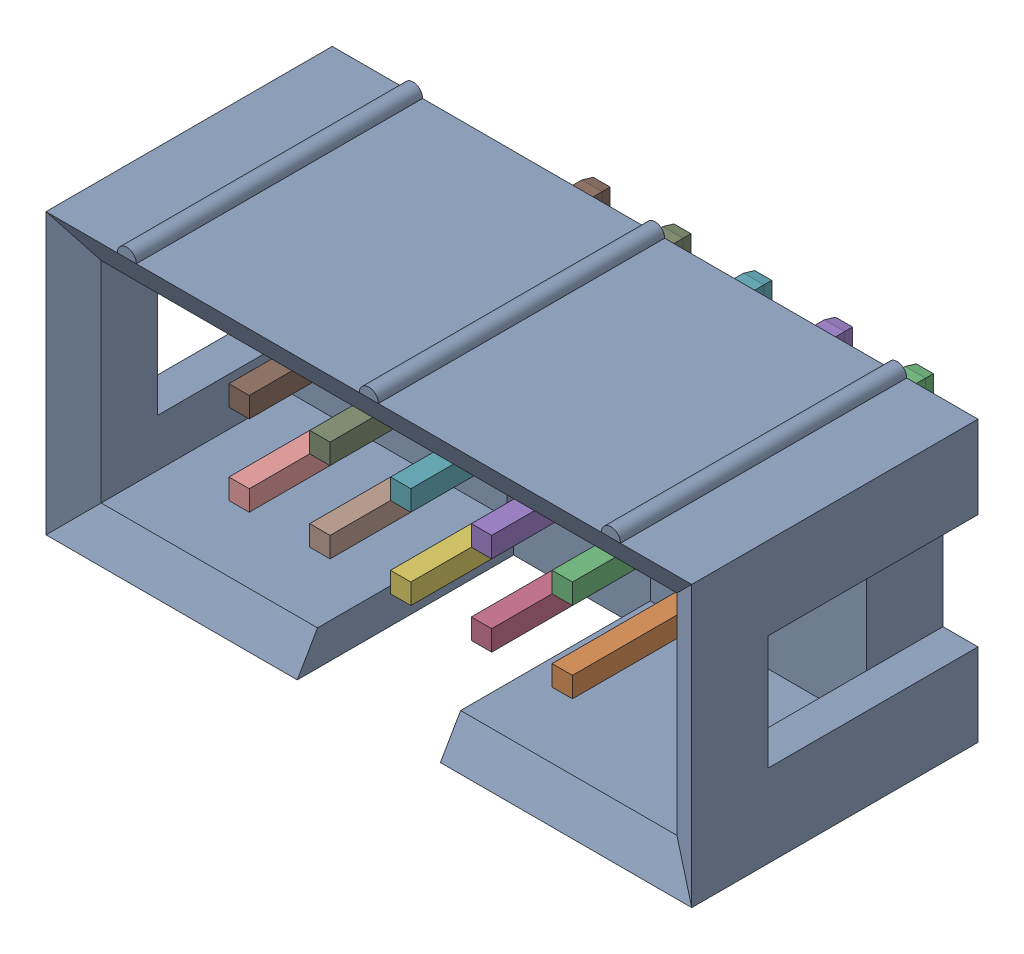
SolidWorks assembly IDC2X5P, configuration ﾃﾞﾌｫﾙﾄ. Lengths in mm.
Overall size (20.3 9.1 12.4).
12 component instances, 2 part files, 0 mates.
Components (placement in the parent):
- User Library-IDC-10M-1: User Library-IDC-10M [ﾃﾞﾌｫﾙﾄ] at origin size (20.3 9.1 12.4)
  - IDC-10M_Body___ _________-1: IDC-10M_Body___ _________ [ﾃﾞﾌｫﾙﾄ] at origin size (20.3 9.1 9.3)
  - IDC_pin___ _________-1: IDC_pin___ _________ [ﾃﾞﾌｫﾙﾄ] at (5.08 -1.27 -3.1) size (0.64 0.64 11.4)
  - IDC_pin___ _________-2: IDC_pin___ _________ [ﾃﾞﾌｫﾙﾄ] at (5.08 1.27 -3.1) size (0.64 0.64 11.4)
  - IDC_pin___ _________-3: IDC_pin___ _________ [ﾃﾞﾌｫﾙﾄ] at (2.54 -1.27 -3.1) size (0.64 0.64 11.4)
  - IDC_pin___ _________-4: IDC_pin___ _________ [ﾃﾞﾌｫﾙﾄ] at (2.54 1.27 -3.1) size (0.64 0.64 11.4)
  - IDC_pin___ _________-5: IDC_pin___ _________ [ﾃﾞﾌｫﾙﾄ] at (0 -1.27 -3.1) size (0.64 0.64 11.4)
  - IDC_pin___ _________-6: IDC_pin___ _________ [ﾃﾞﾌｫﾙﾄ] at (0 1.27 -3.1) size (0.64 0.64 11.4)
  - IDC_pin___ _________-7: IDC_pin___ _________ [ﾃﾞﾌｫﾙﾄ] at (-2.54 -1.27 -3.1) size (0.64 0.64 11.4)
  - IDC_pin___ _________-8: IDC_pin___ _________ [ﾃﾞﾌｫﾙﾄ] at (-2.54 1.27 -3.1) size (0.64 0.64 11.4)
  - IDC_pin___ _________-9: IDC_pin___ _________ [ﾃﾞﾌｫﾙﾄ] at (-5.08 -1.27 -3.1) size (0.64 0.64 11.4)
  - IDC_pin___ _________-10: IDC_pin___ _________ [ﾃﾞﾌｫﾙﾄ] at (-5.08 1.27 -3.1) size (0.64 0.64 11.4)
